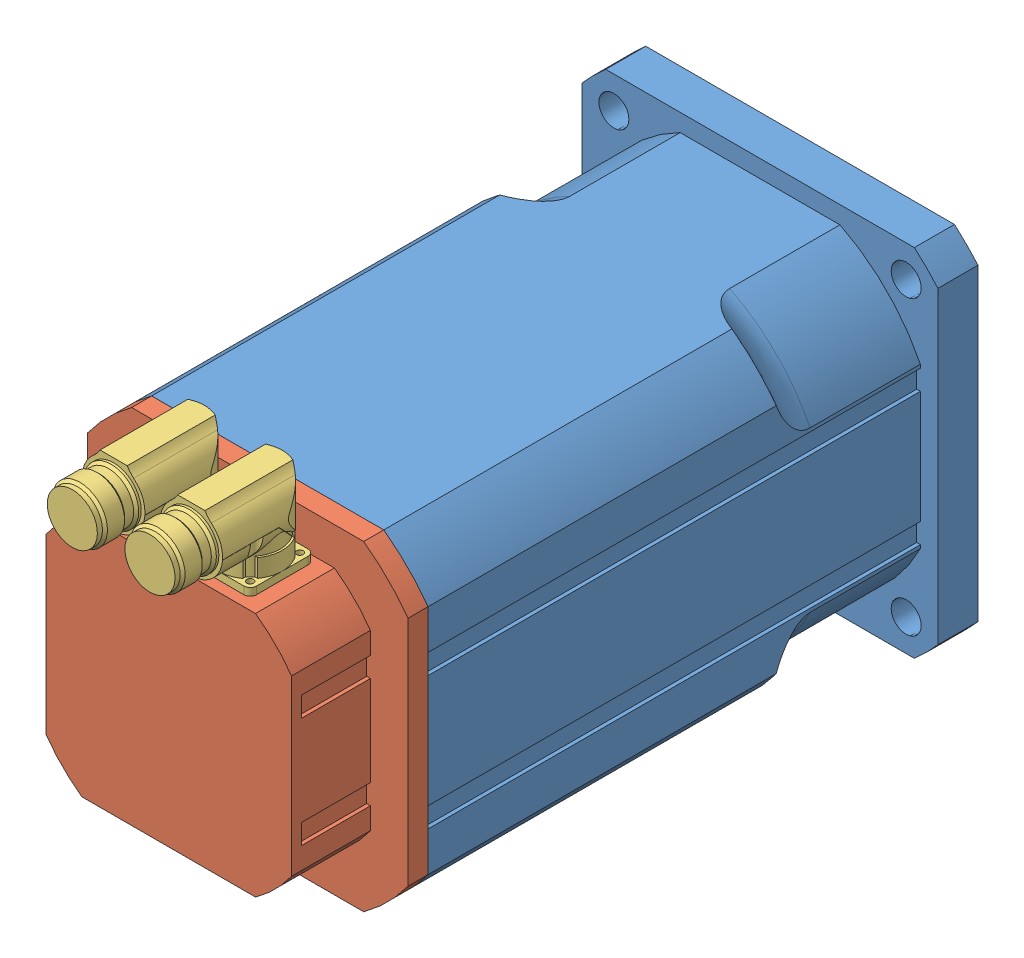
SolidWorks assembly TGN5-1600-KE1 (2), configuration Default. Lengths in mm.
Overall size (142 152 325.19).
5 component instances, 4 part files, 0 mates.
Components (placement in the parent):
- ID_1-1: ID_1 [Default] at (32.5172 -15.1642 -34.4008) size (142 142 262.5)
- ID_1_2-1: ID_1_2 [Default] at (32.5172 -15.1642 74.0992) size (128 128 39.5)
- ID_1_3-1: ID_1_3 [Default] at (59.9765 36.8358 84.088) x (1 0 0) z (0 -1 0) size (25.61 53 32.19)
- ID_1_3-2: ID_1_3 [Default] at (28.9765 36.8358 84.088) x (1 0 0) z (0 -1 0) size (25.61 53 32.19)
- ID_1_4-1: ID_1_4 [Default] at (23.8036 -7.2642 -191.9285) x (-1 0 0) z (0 1 0) size (8 40 7)
